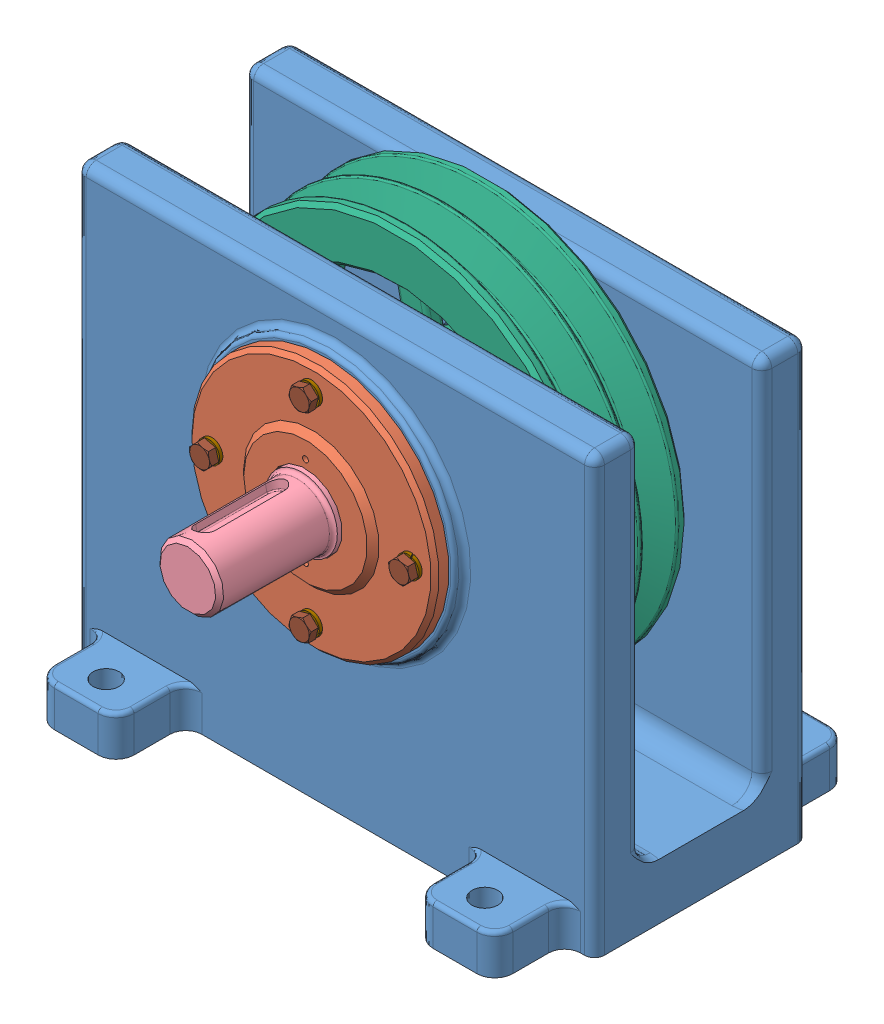
SolidWorks assembly Sestava, configuration Default. Lengths in mm.
Overall size (260 256.8 216).
26 component instances, 11 part files, 30 mates.
Components (placement in the parent):
- 1ZAKLADNA-1: 1ZAKLADNA [Default] at (-24.582 13.7675 203.9312) size (260 218 177)
- 5VICKO-1: 5VICKO [Default] at (105.418 151.7675 264.4312) x (0 0 1) z (-1 0 0) size (20 124 124)
- 4VICKO-1: 4VICKO [Default] at (105.418 151.7675 139.4312) x (-1 0 0) z (0 0 -1) size (128 128 16)
- 3HRIDEL-1: 3HRIDEL [Default] at (105.418 151.7675 331.4312) x (0 0 -1) z (-0.210384 0.977619 0) size (180 52 52)
- PERO ČSN 022562-1: PERO ČSN 022562 [PERO 12e7 x 8 x  36 ČSN 022562] at (109.6467 132.1173 204.4312) x (-0.977619 -0.210384 0) z (0 0 1) size (12 8 36)
- 2REMENICE-1: 2REMENICE [Default] at (105.418 151.7675 203.9312) x (0 0 1) z (0.977619 0.210384 0) size (47 200 200)
- 6KROUZEK-1: 6KROUZEK [Default] at (105.418 151.7675 170.4312) x (0 0 1) z (-1 0 0) size (10 50 50)
- LOŽISKO 60xx ČSN 024630-1: LOŽISKO 60xx ČSN 024630 [LOŽISKO  6008 ČSN 024630] at (105.418 151.7675 162.9312) x (0 0 -1) z (0.446 -0.895033 0) size (15 68 68)
- LOŽISKO 60xx ČSN 024630-2: LOŽISKO 60xx ČSN 024630 [LOŽISKO  6008 ČSN 024630] at (105.418 151.7675 244.9312) x (0 0 -1) z (0.030599 -0.999532 0) size (15 68 68)
- PODLOŽKA ČSN 021741-2: PODLOŽKA ČSN 021741 [PODLOŽKA  6 ČSN 021741] at (105.418 101.7675 269.4312) x (0.968653 -0.248418 0) z (0 0 1) size (11.1 11.1 1.6)
- PODLOŽKA ČSN 021741-3: PODLOŽKA ČSN 021741 [PODLOŽKA  6 ČSN 021741] at (105.418 101.7675 137.8312) size (11.1 11.1 1.6)
- PODLOŽKA ČSN 021741-4: PODLOŽKA ČSN 021741 [PODLOŽKA  6 ČSN 021741] at (55.418 151.7675 137.8312) x (0 -1 0) z (0 0 1) size (11.1 11.1 1.6)
- PODLOŽKA ČSN 021741-5: PODLOŽKA ČSN 021741 [PODLOŽKA  6 ČSN 021741] at (105.418 201.7675 137.8312) x (-1 0 0) z (0 0 1) size (11.1 11.1 1.6)
- PODLOŽKA ČSN 021741-6: PODLOŽKA ČSN 021741 [PODLOŽKA  6 ČSN 021741] at (155.418 151.7675 137.8312) x (0 1 0) z (0 0 1) size (11.1 11.1 1.6)
- PODLOŽKA ČSN 021741-7: PODLOŽKA ČSN 021741 [PODLOŽKA  6 ČSN 021741] at (55.418 151.7675 269.4312) x (-0.248418 -0.968653 0) z (0 0 1) size (11.1 11.1 1.6)
- PODLOŽKA ČSN 021741-8: PODLOŽKA ČSN 021741 [PODLOŽKA  6 ČSN 021741] at (105.418 201.7675 269.4312) x (-0.968653 0.248418 0) z (0 0 1) size (11.1 11.1 1.6)
- PODLOŽKA ČSN 021741-9: PODLOŽKA ČSN 021741 [PODLOŽKA  6 ČSN 021741] at (155.418 151.7675 269.4312) x (0.248418 0.968653 0) z (0 0 1) size (11.1 11.1 1.6)
- GUFERO ČSN 029401-2: GUFERO ČSN 029401 [GUFERO 36x52x7 NBR ČSN 029401] at (105.418 151.7675 259.8812) x (0 0 1) z (-0.809549 0.587053 0) size (7 52 52)
- ŠROUB ČSN EN 24017-4: ŠROUB ČSN EN 24017 [ŠROUB  M6 x 25 ČSN EN 24017] at (105.418 101.7675 275.5312) x (-0.280373 0.959891 0) z (0 0 -1) size (10 11.55 29.5)
- ŠROUB ČSN EN 24017-5: ŠROUB ČSN EN 24017 [ŠROUB  M6 x 25 ČSN EN 24017] at (105.418 101.7675 133.3312) size (10 11.55 29.5)
- ŠROUB ČSN EN 24017-6: ŠROUB ČSN EN 24017 [ŠROUB  M6 x 25 ČSN EN 24017] at (55.418 151.7675 275.5312) x (0.959891 0.280373 0) z (0 0 -1) size (10 11.55 29.5)
- ŠROUB ČSN EN 24017-7: ŠROUB ČSN EN 24017 [ŠROUB  M6 x 25 ČSN EN 24017] at (105.418 201.7675 275.5312) x (0.280373 -0.959891 0) z (0 0 -1) size (10 11.55 29.5)
- ŠROUB ČSN EN 24017-8: ŠROUB ČSN EN 24017 [ŠROUB  M6 x 25 ČSN EN 24017] at (155.418 151.7675 275.5312) x (-0.959891 -0.280373 0) z (0 0 -1) size (10 11.55 29.5)
- ŠROUB ČSN EN 24017-9: ŠROUB ČSN EN 24017 [ŠROUB  M6 x 25 ČSN EN 24017] at (55.418 151.7675 133.3312) x (0 -1 0) z (0 0 1) size (10 11.55 29.5)
- ŠROUB ČSN EN 24017-10: ŠROUB ČSN EN 24017 [ŠROUB  M6 x 25 ČSN EN 24017] at (105.418 201.7675 133.3312) x (-1 0 0) z (0 0 1) size (10 11.55 29.5)
- ŠROUB ČSN EN 24017-11: ŠROUB ČSN EN 24017 [ŠROUB  M6 x 25 ČSN EN 24017] at (155.418 151.7675 133.3312) x (0 1 0) z (0 0 1) size (10 11.55 29.5)
Mates (geometry in assembly coordinates):
- Sjednocená3: coincident anti-aligned: plane of 1ZAKLADNA-1 through (105.418 151.7675 262.4312) normal (0 0 1); plane of 5VICKO-1 through (105.418 213.7675 262.4312) normal (0 0 -1)
- Soustředná3: concentric anti-aligned: circle of 1ZAKLADNA-1; circle of 5VICKO-1
- Soustředná4: concentric aligned: circle of 1ZAKLADNA-1; circle of 5VICKO-1
- Sjednocená5: coincident anti-aligned: plane of 1ZAKLADNA-1 through (105.418 151.7675 145.4312) normal (0 0 -1); plane of 4VICKO-1 through (105.418 215.7675 145.4312) normal (0 0 1)
- Soustředná5: concentric aligned: circle of 1ZAKLADNA-1; circle of 4VICKO-1
- Soustředná6: concentric aligned: circle of 1ZAKLADNA-1; circle of 4VICKO-1
- Soustředná7: concentric anti-aligned: circle of 5VICKO-1; cylinder of 3HRIDEL-1 through (105.418 151.7675 354.0404) axis (0 0 1) radius 18
- Sjednocená7: coincident anti-aligned: plane of 3HRIDEL-1 through (108.8052 136.0278 192.4312) normal (0.210384 -0.977619 0); plane of PERO ČSN 022562-1 through (108.8052 136.0278 192.4312) normal (-0.210384 0.977619 0)
- Sjednocená8: coincident: line of 3HRIDEL-1 through (115.5176 133.3556 216.4312) axis (0 0 -1); plane of PERO ČSN 022562-1 through (116.354 129.4692 192.4312) normal (0.977619 0.210384 0)
- Soustředná8: concentric anti-aligned: cylinder of 3HRIDEL-1 through (108.8052 136.0278 216.4312) axis (0.210384 -0.977619 0) radius 6; cylinder of PERO ČSN 022562-1 through (110.4882 128.2069 216.4312) axis (-0.210384 0.977619 0) radius 6
- Soustředná9: concentric anti-aligned: cylinder of 3HRIDEL-1 through (105.418 151.7675 354.0404) axis (0 0 1) radius 21; cylinder of 2REMENICE-1 through (105.418 151.7675 157.678) axis (0 0 -1) radius 21
- Sjednocená10: coincident anti-aligned: plane of 3HRIDEL-1 through (79.9999 146.2975 227.4312) normal (0 0 -1); plane of 2REMENICE-1 through (112.3607 119.5061 227.4312) normal (0 0 1)
- Rovnoběžná2: parallel anti-aligned: plane of PERO ČSN 022562-1 through (116.354 129.4692 192.4312) normal (0.977619 0.210384 0); plane of 2REMENICE-1 through (116.0063 129.3944 227.4322) normal (-0.977619 -0.210384 0)
- Soustředná10: concentric anti-aligned: cylinder of 3HRIDEL-1 through (105.418 151.7675 354.0404) axis (0 0 1) radius 20; cylinder of 6KROUZEK-1 through (105.418 151.7675 170.4312) axis (0 0 -1) radius 20
- Sjednocená12: coincident anti-aligned: plane of 2REMENICE-1 through (112.3607 119.5061 180.4312) normal (0 0 -1); plane of 6KROUZEK-1 through (105.418 176.7675 180.4312) normal (0 0 1)
- Soustředná11: concentric anti-aligned: cylinder of 3HRIDEL-1 through (105.418 151.7675 354.0404) axis (0 0 1) radius 20; cylinder of LOŽISKO 60xx ČSN 024630-1 through (105.418 151.7675 162.9312) axis (0 0 -1) radius 20
- Sjednocená13: coincident anti-aligned: plane of 6KROUZEK-1 through (105.418 171.7675 170.4312) normal (0 0 -1); plane of LOŽISKO 60xx ČSN 024630-1 through (123.3187 160.6875 170.4312) normal (0 0 1)
- Soustředná12: concentric anti-aligned: cylinder of 3HRIDEL-1 through (105.418 151.7675 354.0404) axis (0 0 1) radius 20; cylinder of LOŽISKO 60xx ČSN 024630-2 through (105.418 151.7675 244.9312) axis (0 0 -1) radius 20
- Sjednocená14: coincident anti-aligned: plane of 3HRIDEL-1 through (85.8656 147.5598 237.4312) normal (0 0 1); plane of LOŽISKO 60xx ČSN 024630-2 through (125.4086 152.3795 237.4312) normal (0 0 -1)
- Sjednocená15: coincident anti-aligned: plane of 5VICKO-1 through (105.418 185.7675 252.4312) normal (0 0 -1); plane of LOŽISKO 60xx ČSN 024630-2 through (139.4021 152.8078 252.4312) normal (0 0 1)
- Sjednocená28: coincident anti-aligned: plane of 5VICKO-1 through (105.418 213.7675 269.4312) normal (0 0 1); plane of PODLOŽKA ČSN 021741-2 through (105.418 101.7675 269.4312) normal (0 0 -1)
- Sjednocená30: coincident anti-aligned: plane of 4VICKO-1 through (105.418 215.7675 139.4312) normal (0 0 -1); plane of PODLOŽKA ČSN 021741-3 through (105.418 101.7675 139.4312) normal (0 0 1)
- Soustředná251: concentric aligned: cylinder of GUFERO ČSN 029401-2 through (105.418 151.7675 259.8812) axis (0 0 -1) radius 26; circle of 5VICKO-1
- Sjednocená33: coincident anti-aligned: plane of 5VICKO-1 through (105.418 177.7675 264.4312) normal (0 0 -1); plane of GUFERO ČSN 029401-2 through (120.6814 172.8157 264.4312) normal (0 0 1)
- Soustředná261: concentric aligned: circle of 1ZAKLADNA-1; cylinder of ŠROUB ČSN EN 24017-4 through (105.418 101.7675 246.0312) axis (0 0 1) radius 3
- Sjednocená341: coincident anti-aligned: plane of PODLOŽKA ČSN 021741-2 through (105.418 101.7675 271.0312) normal (0 0 1); circle of ŠROUB ČSN EN 24017-4
- Soustředná271: concentric aligned: circle of 1ZAKLADNA-1; cylinder of ŠROUB ČSN EN 24017-5 through (105.418 101.7675 162.8312) axis (0 0 -1) radius 3
- Sjednocená351: coincident anti-aligned: plane of PODLOŽKA ČSN 021741-3 through (105.418 101.7675 137.8312) normal (0 0 -1); plane of ŠROUB ČSN EN 24017-5 through (105.418 101.7675 137.8312) normal (0 0 1)
- Soustředná321: concentric aligned: circle of PODLOŽKA ČSN 021741-3; circle of ŠROUB ČSN EN 24017-5
- Soustředná322: concentric anti-aligned: circle of PODLOŽKA ČSN 021741-2; circle of ŠROUB ČSN EN 24017-4
